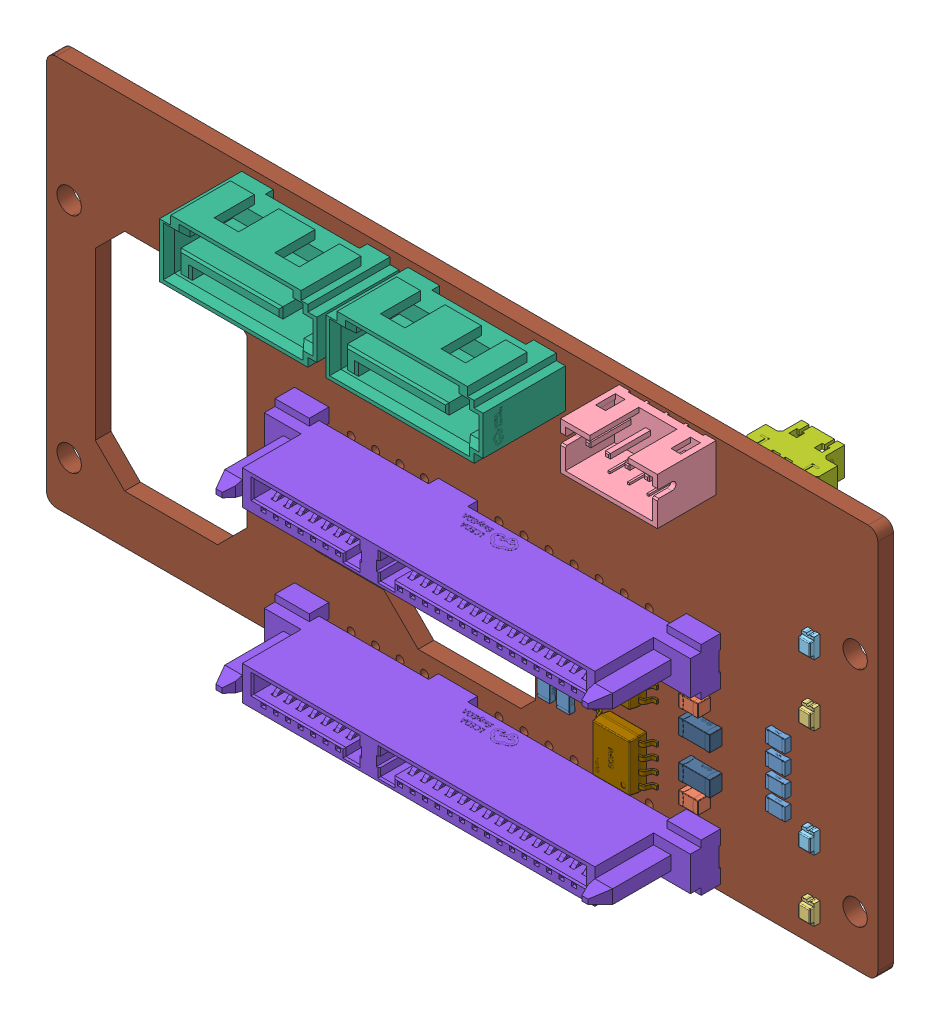
SolidWorks assembly 3D_M68SPRO 2backplane V1.0_2023-03-09, configuration 默认. Lengths in mm.
Overall size (84.97 40.16 17.2).
74 component instances, 11 part files, 0 mates.
Components (placement in the parent):
- 3D_M68SPRO 2backplane V1.0_2023-03-09.step-1: 3D_M68SPRO 2backplane V1.0_2023-03-09.step [默认] at origin size (84.97 40.16 17.2)
  - R5.step-1: R5.step [默认] at (75.1002 16.7 1.6001) size (2 1.3 0.61)
    - R0805.step-1: R0805.step [默认] at origin size (2 1.3 0.61)
      - COMPOUND.step-1: COMPOUND.step [默认] at origin size (2 1.3 0.61)
  - R6.step-1: R6.step [默认] at (75.1002 14.7 1.6001) size (2 1.3 0.61)
    - R0805.step-1: R0805.step [默认] at origin size (2 1.3 0.61)
      - COMPOUND.step-1: COMPOUND.step [默认] at origin size (2 1.3 0.61)
  - R7.step-1: R7.step [默认] at (75.1002 12.7 1.6001) size (2 1.3 0.61)
    - R0805.step-1: R0805.step [默认] at origin size (2 1.3 0.61)
      - COMPOUND.step-1: COMPOUND.step [默认] at origin size (2 1.3 0.61)
  - R8.step-1: R8.step [默认] at (75.1002 10.7 1.6001) size (2 1.3 0.61)
    - R0805.step-1: R0805.step [默认] at origin size (2 1.3 0.61)
      - COMPOUND.step-1: COMPOUND.step [默认] at origin size (2 1.3 0.61)
  - R2.step-1: R2.step [默认] at (53.4001 14.1 1.6001) x (0 1 0) z (0 0 1) size (2 1.3 0.61)
    - R0805.step-1: R0805.step [默认] at origin size (2 1.3 0.61)
      - COMPOUND.step-1: COMPOUND.step [默认] at origin size (2 1.3 0.61)
  - R4.step-1: R4.step [默认] at (53.4001 9.5 1.6001) x (0 -1 0) z (0 0 1) size (2 1.3 0.61)
    - R0805.step-1: R0805.step [默认] at origin size (2 1.3 0.61)
      - COMPOUND.step-1: COMPOUND.step [默认] at origin size (2 1.3 0.61)
  - R1.step-1: R1.step [默认] at (51.4001 14.1 1.6001) x (0 1 0) z (0 0 1) size (2 1.3 0.61)
    - R0805.step-1: R0805.step [默认] at origin size (2 1.3 0.61)
      - COMPOUND.step-1: COMPOUND.step [默认] at origin size (2 1.3 0.61)
  - R3.step-1: R3.step [默认] at (51.4001 9.5 1.6001) x (0 -1 0) z (0 0 1) size (2 1.3 0.61)
    - R0805.step-1: R0805.step [默认] at origin size (2 1.3 0.61)
      - COMPOUND.step-1: COMPOUND.step [默认] at origin size (2 1.3 0.61)
  - C1.step-1: C1.step [默认] at (66.9002 16.1 1.6001) x (-1 0 0) z (0 0 1) size (2 1.3 1.3)
    - C0805.step-1: C0805.step [默认] at origin size (2 1.3 1.3)
      - SOLID.step-1: SOLID.step [默认] at origin size (2 1.3 1.3)
  - C3.step-1: C3.step [默认] at (66.9002 7.5 1.6001) x (-1 0 0) z (0 0 1) size (2 1.3 1.3)
    - C0805.step-1: C0805.step [默认] at origin size (2 1.3 1.3)
      - SOLID.step-1: SOLID.step [默认] at origin size (2 1.3 1.3)
  - LED1.step-1: LED1.step [默认] at (78.4502 20.6001 1.6001) x (0 1 0) z (0 0 1) size (2.02 1.26 1.01)
    - LED0805-RD_BLUE.step-1: LED0805-RD_BLUE.step [默认] at origin size (2.02 1.26 1.01)
      - COMPOUND-0.step-1: COMPOUND-0.step [默认] at origin size (2.02 1.26 1.01)
  - LED3.step-1: LED3.step [默认] at (78.4502 3.3 1.6001) x (0 1 0) z (0 0 1) size (2.02 1.26 1.01)
    - LED0805-RD_BLUE.step-1: LED0805-RD_BLUE.step [默认] at origin size (2.02 1.26 1.01)
      - COMPOUND-0.step-1: COMPOUND-0.step [默认] at origin size (2.02 1.26 1.01)
  - CN1.step-1: CN1.step [默认] at (63.5002 38.0001 1.6001) x (-1 0 0) z (0 0 1) size (9.9 4.8 9.4)
    - CONN-TH_4P-P2.00_PH-4A-RED.step-1: CONN-TH_4P-P2.00_PH-4A-RED.step [默认] at origin size (9.9 4.8 9.4)
      - COMPOUND-1.step-1: COMPOUND-1.step [默认] at origin size (9.9 4.8 9.4)
  - LED4.step-1: LED4.step [默认] at (78.4502 9.6 1.6001) x (0 1 0) z (0 0 1) size (2.02 1.26 1.01)
    - LED0805-RD_RED.step-1: LED0805-RD_RED.step [默认] at origin size (2.02 1.26 1.01)
      - COMPOUND-2.step-1: COMPOUND-2.step [默认] at origin size (2.02 1.26 1.01)
  - LED2.step-1: LED2.step [默认] at (78.4502 26.9001 1.6001) x (0 1 0) z (0 0 1) size (2.02 1.26 1.01)
    - LED0805-RD_RED.step-1: LED0805-RD_RED.step [默认] at origin size (2.02 1.26 1.01)
      - COMPOUND-2.step-1: COMPOUND-2.step [默认] at origin size (2.02 1.26 1.01)
  - S1.step-1: S1.step [默认] at (45.0001 36.5001 1.6001) size (16.08 6.45 11.5)
    - CONN-TH_SATA7P.step-1: CONN-TH_SATA7P.step [默认] at origin size (16.08 6.45 11.5)
      - COMPOUND-3.step-1: COMPOUND-3.step [默认] at origin size (16.08 6.45 11.5)
  - S2.step-1: S2.step [默认] at (28.0001 36.5001 1.6001) size (16.08 6.45 11.5)
    - CONN-TH_SATA7P.step-1: CONN-TH_SATA7P.step [默认] at origin size (16.08 6.45 11.5)
      - COMPOUND-3.step-1: COMPOUND-3.step [默认] at origin size (16.08 6.45 11.5)
  - CN2.step-1: CN2.step [默认] at (73.0001 37.0001 0) x (1 0 0) z (0 0 -1) size (7.35 4.2 4.8)
    - CONN-SMD_2P-P1.25-MX1.25-2P-LT.step-1: CONN-SMD_2P-P1.25-MX1.25-2P-LT.step [默认] at origin size (7.35 4.2 4.8)
      - COMPOUND-4.step-1: COMPOUND-4.step [默认] at origin size (7.35 4.2 4.8)
  - SATA1.step-1: SATA1.step [默认] at (47.1001 20.43 1.6001) size (43.56 4.9 13.8)
    - SATA__________________________________________.step-1: SATA__________________________________________.step [默认] at origin size (43.56 4.9 13.8)
      - SOLID-5.step-1: SOLID-5.step [默认] at origin size (43.56 4.9 13.8)
  - SATA2.step-1: SATA2.step [默认] at (47.1001 3.12 1.6001) size (43.56 4.9 13.8)
    - SATA__________________________________________.step-1: SATA__________________________________________.step [默认] at origin size (43.56 4.9 13.8)
      - SOLID-5.step-1: SOLID-5.step [默认] at origin size (43.56 4.9 13.8)
  - Q2.step-1: Q2.step [默认] at (59.5001 8 1.6001) x (0 1 0) z (0 0 1) size (5 6.2 1.8)
    - SOP-8_L5.0-W4.0-P1.27-LS6.0-BL.step-1: SOP-8_L5.0-W4.0-P1.27-LS6.0-BL.step [默认] at origin size (5 6.2 1.8)
      - COMPOUND-6.step-1: COMPOUND-6.step [默认] at origin size (5 6.2 1.8)
  - Q1.step-1: Q1.step [默认] at (59.5001 15.6 1.6001) x (0 1 0) z (0 0 1) size (5 6.2 1.8)
    - SOP-8_L5.0-W4.0-P1.27-LS6.0-BL.step-1: SOP-8_L5.0-W4.0-P1.27-LS6.0-BL.step [默认] at origin size (5 6.2 1.8)
      - COMPOUND-6.step-1: COMPOUND-6.step [默认] at origin size (5 6.2 1.8)
  - C2.step-1: C2.step [默认] at (67.5002 13.8 1.6001) size (3.2 1.6 1.3)
    - C1206.step-1: C1206.step [默认] at origin size (3.2 1.6 1.3)
      - SOLID-7.step-1: SOLID-7.step [默认] at origin size (3.2 1.6 1.3)
  - C4.step-1: C4.step [默认] at (67.5002 9.8 1.6001) size (3.2 1.6 1.3)
    - C1206.step-1: C1206.step [默认] at origin size (3.2 1.6 1.3)
      - SOLID-7.step-1: SOLID-7.step [默认] at origin size (3.2 1.6 1.3)
  - COMPOUND-8.step-1: COMPOUND-8.step [默认] at origin size (84.97 39.97 1.6)
